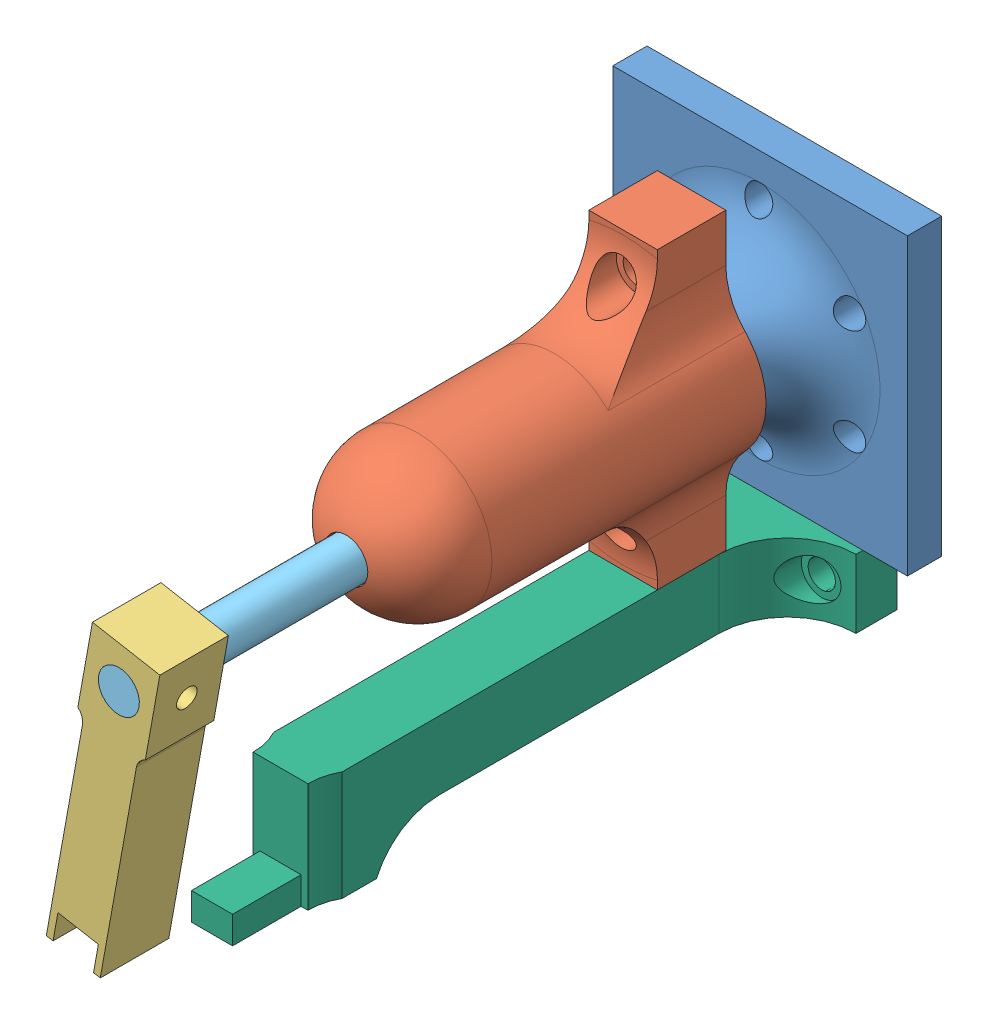
SolidWorks assembly Assem1, configuration Default. Lengths in mm.
Overall size (43 59.29 98.6).
7 component instances, 7 part files, 15 mates.
Components (placement in the parent):
- Base Lock-1: Base Lock [Default] at (29.073 30.6635 20.5474) size (43 43 35)
- Lock Cover-1: Lock Cover [Default] at (29.073 30.6635 30.5474) size (21.75 43 50.41)
- Moving Arm-1: Moving Arm [Default] at (29.073 30.6635 104.1427) x (0.984145 -0.177368 0) z (0 0 1) size (10 43.5 10)
- Sliding key-1: Sliding key [Default] at (29.073 30.6635 74.1427) x (-0.984145 0.177368 0) z (0 0 -1) size (15 15 30)
- Rod-1: Rod [Default] at (29.073 30.6635 64.1427) x (0.984145 -0.177368 0) z (0 0 1) size (6 6 50)
- Base Arm-1: Base Arm [Default] at (29.073 4.1635 21.5474) x (-1 0 0) z (0 0 1) size (30 16 85)
- Temple support-1: Temple support [Default] at (0 0 15.5474) x (-1 0 0) z (0 0 -1) (suppressed, hidden)
Mates (geometry in assembly coordinates):
- Parallel1: parallel: plane of Base Lock-1 through (29.073 36.6635 50.5474) normal (0 -1 0); plane of Sliding key-1
- Concentric4: concentric: cylinder of Base Lock-1 through (29.073 30.6635 50.5474) axis (0 0 -1) radius 7.5; cylinder of Sliding key-1 through (29.073 30.6635 54.1427) axis (0 0 1) radius 4.365
- Concentric5: concentric: cylinder of Base Lock-1 through (29.073 30.6635 50.5474) axis (0 0 -1) radius 7.5; cylinder of Lock Cover-1 through (29.073 30.6635 70.5474) axis (0 0 -1) radius 10.875
- Concentric6: concentric: cylinder of Base Lock-1 through (29.073 30.6635 50.5474) axis (0 0 -1) radius 7.5; cylinder of Moving Arm-1 through (29.073 30.6635 114.1427) axis (0 0 -1) radius 3
- Concentric7: concentric: cylinder of Base Lock-1 through (29.073 46.1635 15.5474) axis (0 0 1) radius 2; cylinder of Lock Cover-1 through (29.073 46.1635 40.5474) axis (0 0 -1) radius 2
- Distance1: distance = 10 mm: plane of Lock Cover-1 through (29.073 30.6635 30.5474) normal (0 0 -1); plane of Base Lock-1 through (29.073 30.6635 20.5474) normal (0 0 1)
- Concentric8: concentric: cylinder of Moving Arm-1 through (29.073 30.6635 114.1427) axis (0 0 -1) radius 3; cylinder of Rod-1 through (29.073 30.6635 114.1427) axis (0 0 -1) radius 3
- Concentric9: concentric: cylinder of Moving Arm-1 through (33.9938 29.7767 109.1427) axis (-0.984145 0.177368 0) radius 1.5; cylinder of Rod-1 through (26.1206 31.1956 109.1427) axis (0.984145 -0.177368 0) radius 1.5
- Concentric10: concentric: cylinder of Sliding key-1 through (23.1682 31.7277 69.1427) axis (0.984145 -0.177368 0) radius 1.5; cylinder of Rod-1 through (26.1206 31.1956 69.1427) axis (0.984145 -0.177368 0) radius 1.5
- Coincident1: coincident: plane of Base Lock-1 through (29.073 30.6635 15.5474) normal (0 0 -1); plane of Base Arm-1 through (29.073 4.1635 15.5474) normal (0 0 -1)
- Parallel2: parallel: plane of Base Lock-1 through (50.573 52.1635 15.5474) normal (1 0 0); plane of Base Arm-1 through (44.073 9.1635 15.5474) normal (1 0 0)
- Coincident2: coincident: plane of Base Lock-1 through (50.573 9.1635 15.5474) normal (0 -1 0); plane of Base Arm-1 through (34.073 9.1635 86.5474) normal (0 1 0)
- Width2: width: plane of Base Lock-1 through (50.573 52.1635 15.5474) normal (1 0 0); plane of Base Lock-1 through (7.573 52.1635 15.5474) normal (-1 0 0); plane of Base Arm-1 through (14.073 9.1635 15.5474) normal (-1 0 0); plane of Base Arm-1 through (44.073 9.1635 15.5474) normal (1 0 0)
- Coincident5: coincident: circle of Base Lock-1; circle of Temple support-1
- Parallel4: parallel: plane of Base Lock-1 through (50.573 52.1635 15.5474) normal (0 1 0); plane of Temple support-1 through (0 52.1635 12.5474) normal (0 1 0)
